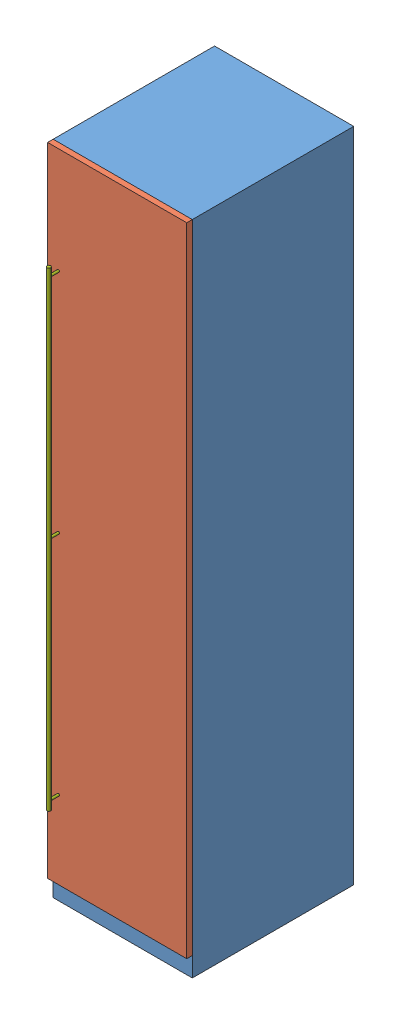
SolidWorks assembly PAX-Eingang, configuration Standard. Lengths in mm.
Overall size (500 2360 641).
9 component instances, 7 part files, 25 mates.
Components (placement in the parent):
- Pax-Korpus-Kleiderschrank-236-1: Pax-Korpus-Kleiderschrank-236 [Standard] at (-247.5936 -1124.7676 2360) size (500 2360 580)
- BALLSTAD-Tür-229-1: BALLSTAD-Tür-229 [Standard] at (-247.5936 90.2324 2650) size (500 2290 20)
- KOMPLEMENT-Regalbode-1: KOMPLEMENT-Regalbode [Standard] at (-247.5936 895.2324 2365) size (480 10 570)
- KOMPLEMENT-Kleiderstange-1: KOMPLEMENT-Kleiderstange [Standard] at (-487.5936 830.2324 2335) size (480 50 30)
- KOMPLEMENT-Regalbode-2: KOMPLEMENT-Regalbode [Standard] at (-247.5936 -434.7676 2365) size (480 10 570)
- KOMPLIMENT-Schublade-1: KOMPLIMENT-Schublade [Standard] at (-247.5936 -604.7676 2365) size (480 160 570)
- KOMPLEMENT-Netzdrahtkorb-1: KOMPLEMENT-Netzdrahtkorb [Standard] at (-247.5936 -894.7676 2365) size (480 160 570)
- KOMPLEMENT-Regalbode-3: KOMPLEMENT-Regalbode [Standard] at (-247.5936 -274.7676 2365) size (480 10 570)
- LANSA-1: LANSA [Standard] at (-458.5936 -804.7676 2704.5) x (0 0 -1) z (1 0 0) size (41 1690 13)
Mates (geometry in assembly coordinates):
- Deckungsgleich1: coincident aligned: plane of Pax-Korpus-Kleiderschrank-236-1 through (-247.5936 1235.2324 2360) normal (0 1 0); plane of BALLSTAD-Tür-229-1 through (-497.5936 1235.2324 2670) normal (0 1 0)
- Deckungsgleich2: coincident anti-aligned: plane of Pax-Korpus-Kleiderschrank-236-1 through (-497.5936 -1114.7676 2650) normal (0 0 1); plane of BALLSTAD-Tür-229-1 through (-247.5936 90.2324 2650) normal (0 0 -1)
- Deckungsgleich3: coincident aligned: plane of Pax-Korpus-Kleiderschrank-236-1 through (-497.5936 -1114.7676 2650) normal (-1 0 0); plane of BALLSTAD-Tür-229-1 through (-497.5936 -1054.7676 2670) normal (-1 0 0)
- Deckungsgleich4: coincident anti-aligned: plane of Pax-Korpus-Kleiderschrank-236-1 through (-487.5936 1225.2324 2080) normal (0 0 1); plane of KOMPLEMENT-Regalbode-1 through (-487.5936 905.2324 2080) normal (0 0 -1)
- Deckungsgleich5: coincident anti-aligned: plane of Pax-Korpus-Kleiderschrank-236-1 through (-487.5936 1225.2324 2650) normal (1 0 0); plane of KOMPLEMENT-Regalbode-1 through (-487.5936 905.2324 2650) normal (-1 0 0)
- Abstand1: distance = 320 mm anti-aligned: plane of KOMPLEMENT-Regalbode-1 through (-247.5936 905.2324 2365) normal (0 1 0); plane of Pax-Korpus-Kleiderschrank-236-1 through (-247.5936 1225.2324 2360) normal (0 -1 0)
- Deckungsgleich7: coincident anti-aligned: plane of Pax-Korpus-Kleiderschrank-236-1 through (-487.5936 1225.2324 2650) normal (1 0 0); plane of KOMPLEMENT-Kleiderstange-1 through (-487.5936 830.2324 2335) normal (-1 0 0)
- Abstand2: distance = 50 mm anti-aligned: plane of KOMPLEMENT-Kleiderstange-1 through (-467.5936 845.2324 2320) normal (0 1 0); plane of KOMPLEMENT-Regalbode-1 through (-247.5936 895.2324 2365) normal (0 -1 0)
- Abstand3: distance = 300 mm aligned: plane of KOMPLEMENT-Kleiderstange-1 through (-467.5936 795.2324 2350) normal (0 0 1); plane of Pax-Korpus-Kleiderschrank-236-1 through (-497.5936 -1114.7676 2650) normal (0 0 1)
- Deckungsgleich10: coincident anti-aligned: plane of Pax-Korpus-Kleiderschrank-236-1 through (-487.5936 1225.2324 2080) normal (0 0 1); plane of KOMPLEMENT-Regalbode-2 through (-487.5936 -424.7676 2080) normal (0 0 -1)
- Deckungsgleich11: coincident anti-aligned: plane of Pax-Korpus-Kleiderschrank-236-1 through (-487.5936 1225.2324 2650) normal (1 0 0); plane of KOMPLEMENT-Regalbode-2 through (-487.5936 -424.7676 2650) normal (-1 0 0)
- Abstand4: distance = 1220 mm anti-aligned: plane of KOMPLEMENT-Kleiderstange-1 through (-467.5936 795.2324 2320) normal (0 -1 0); plane of KOMPLEMENT-Regalbode-2 through (-247.5936 -424.7676 2365) normal (0 1 0)
- Deckungsgleich13: coincident anti-aligned: plane of Pax-Korpus-Kleiderschrank-236-1 through (-487.5936 1225.2324 2080) normal (0 0 1); plane of KOMPLIMENT-Schublade-1 through (-487.5936 -594.7676 2080) normal (0 0 -1)
- Deckungsgleich14: coincident anti-aligned: plane of Pax-Korpus-Kleiderschrank-236-1 through (-487.5936 1225.2324 2650) normal (1 0 0); plane of KOMPLIMENT-Schublade-1 through (-487.5936 -594.7676 2650) normal (-1 0 0)
- Abstand5: distance = 10 mm anti-aligned: plane of KOMPLIMENT-Schublade-1 through (-247.5936 -444.7676 2365) normal (0 1 0); plane of KOMPLEMENT-Regalbode-2 through (-247.5936 -434.7676 2365) normal (0 -1 0)
- Deckungsgleich16: coincident anti-aligned: plane of Pax-Korpus-Kleiderschrank-236-1 through (-247.5936 -1054.7676 2360) normal (0 1 0); plane of KOMPLEMENT-Netzdrahtkorb-1 through (-247.5936 -1054.7676 2365) normal (0 -1 0)
- Deckungsgleich17: coincident: plane of Pax-Korpus-Kleiderschrank-236-1 through (-487.5936 1225.2324 2650) normal (1 0 0); line of KOMPLEMENT-Netzdrahtkorb-1 through (-487.5936 -894.7676 2080) axis (0 0 1)
- Deckungsgleich18: coincident: plane of Pax-Korpus-Kleiderschrank-236-1 through (-487.5936 1225.2324 2080) normal (0 0 1); line of KOMPLEMENT-Netzdrahtkorb-1 through (-7.5936 -894.7676 2080) axis (-1 0 0)
- Deckungsgleich19: coincident anti-aligned: plane of Pax-Korpus-Kleiderschrank-236-1 through (-7.5936 1225.2324 2080) normal (-1 0 0); plane of KOMPLEMENT-Regalbode-3 through (-7.5936 -264.7676 2650) normal (1 0 0)
- Deckungsgleich20: coincident anti-aligned: plane of Pax-Korpus-Kleiderschrank-236-1 through (-487.5936 1225.2324 2080) normal (0 0 1); plane of KOMPLEMENT-Regalbode-3 through (-487.5936 -264.7676 2080) normal (0 0 -1)
- Abstand7: distance = 150 mm anti-aligned: plane of KOMPLEMENT-Regalbode-3 through (-247.5936 -274.7676 2365) normal (0 -1 0); plane of KOMPLEMENT-Regalbode-2 through (-247.5936 -424.7676 2365) normal (0 1 0)
- Deckungsgleich21: coincident anti-aligned: plane of BALLSTAD-Tür-229-1 through (-247.5936 90.2324 2670) normal (0 0 1); plane of LANSA-1 through (-458.5936 855.2324 2670) normal (0 0 -1)
- Parallel1: parallel aligned: line of BALLSTAD-Tür-229-1 through (-497.5936 1235.2324 2670) axis (0 -1 0); cylinder of LANSA-1 through (-458.5936 885.2324 2704.5) axis (0 -1 0) radius 6.5
- Abstand8: distance = 250 mm aligned: plane of LANSA-1 through (-458.5936 -804.7676 2704.5) normal (0 -1 0); plane of BALLSTAD-Tür-229-1 through (-497.5936 -1054.7676 2670) normal (0 -1 0)
- Abstand9: distance = 35 mm: cylinder of LANSA-1 through (-458.5936 -774.7676 2670) axis (0 0 1) radius 4; line of BALLSTAD-Tür-229-1 through (-497.5936 1235.2324 2670) axis (0 -1 0)
